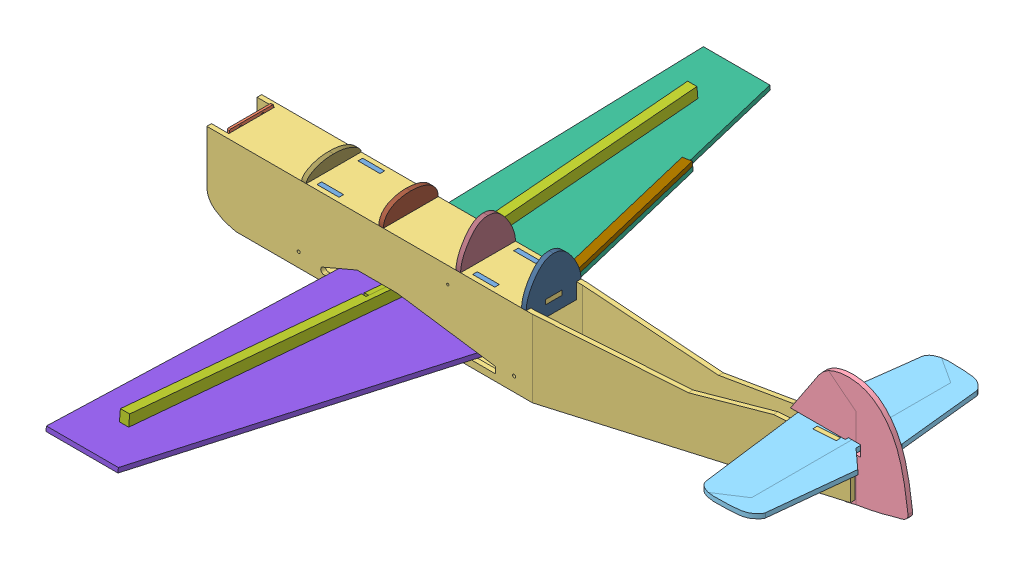
SolidWorks assembly BF109, configuration Default. Lengths in mm.
Overall size (779.28 215.67 760.08).
18 component instances, 14 part files, 17 mates.
Components (placement in the parent):
- Swappable Power Pod-1: Swappable Power Pod [Default] at origin size (334.33 44.96 52.58)
  - Swappable Power Pod-1: Swappable Power Pod [Default] at origin size (331.79 41.45 52.58)
  - 3D Printed Firewall-1: 3D Printed Firewall [Default] at (-149.3838 22.733 0) x (0 0 -1) z (0 -1 0) size (50.8 27.94 44.45)
- BF109_Fuselage-1: BF109_Fuselage [Default] at (-166.8438 41.4528 26.289) size (717.99 114.65 63.25)
- BF109_Tail-1: BF109_Tail [Default] at (474.0399 63.7309 0) size (135.74 127.69 270.43)
  - BF109_Rudder-1: BF109_Rudder [Default] at origin size (135.74 127.69 5.33)
  - BF109_Elevator-1: BF109_Elevator [Default] at (10.9958 -1.327 0) size (91.95 5.33 270.43)
- Part5^BF109-1: Part5^BF109 [Default] at origin size (2138.67 989.27 0) (hidden, virtual)
- BF109_Wing-1: BF109_Wing [Default] at (-25.8538 -41.5889 0) x (0 0.087156 -0.996195) z (1 0 0) size (755.05 90.58 170.24)
  - BF109_RightWing-1: BF109_RightWing [Default] at origin size (380.42 5.33 170.24)
  - BF109_Spar-1: BF109_Spar [Default] at origin size (375.56 25.75 10.67)
  - BF109_LeftWing-1: BF109_LeftWing [Default] at (0.9262 5.253 0) x (-0.984808 0.173648 0) z (0 0 1) size (380.42 5.33 170.24)
  - BF109_Spar-2: BF109_Spar [Default] at (0 0 119.8911) x (-0.984808 0.173648 0) z (0 0 -1) size (375.56 25.75 10.67)
  - BF109_WingSpacer-1: BF109_WingSpacer [Default] at (0 5.334 0) x (1 0 0) z (0 1 0) size (266.31 56.08 5.33)
- Former1-1: Former1 [Default] at (195.7891 41.4528 26.289) x (0 0 -1) z (1 0 0) size (63.25 59.44 5.33)
- Former3-1: Former3 [Default] at (31.2997 0 0) x (0 0 -1) z (1 0 0) size (63.25 26.92 5.33)
- Former4-1: Former4 [Default] at (-57.6003 0 0) x (0 0 -1) z (1 0 0) size (63.25 19.3 5.33)
- Former2-1: Former2 [Default] at (120.1997 41.4528 26.289) x (0 0 -1) z (1 0 0) size (63.25 46.74 5.33)
Mates (geometry in assembly coordinates):
- Coincident2: coincident anti-aligned: plane of Swappable Power Pod-1/Swappable Power Pod-1 through (-146.8438 5.334 26.289) normal (0 0 1); plane of BF109_Fuselage-1 through (-166.8438 41.4528 26.289) normal (0 0 -1)
- Coincident4: coincident aligned: plane of BF109_Tail-1/BF109_Rudder-1 through (474.0399 63.7309 0) normal (0 0 1); plane of assembly through (0 0 0) normal (0 0 1)
- Coincident5: coincident anti-aligned: plane of BF109_Fuselage-1 through (-165.0687 62.4039 52.0333) normal (0 1 0); plane of BF109_Tail-1/BF109_Elevator-1 through (485.0356 62.4039 0) normal (0 -1 0)
- Distance2: distance = 1.27 mm: line of BF109_Tail-1/BF109_Rudder-1 through (552.0566 8.8195 2.667) axis (0 1 0); plane of BF109_Fuselage-1 through (550.7841 41.4528 2.675) normal (0.997631 0 -0.068787)
- Coincident6: coincident anti-aligned: plane of Swappable Power Pod-1/3D Printed Firewall-1 through (-146.8438 1.778 24.13) normal (1 0 0); plane of BF109_Fuselage-1 through (-146.8438 36.1188 26.289) normal (-1 0 0)
- Distance5: distance = 1.905 mm aligned: plane of Swappable Power Pod-1/3D Printed Firewall-1 through (-146.8438 44.958 24.13) normal (0 1 0); plane of BF109_Fuselage-1 through (-166.8438 43.053 31.623) normal (0 1 0)
- Coincident9: coincident: line of BF109_Fuselage-1 through (-31.7768 -39.289 -26.289) axis (1 0 0); plane of BF109_Wing-1/BF109_RightWing-1 through (-25.8538 -41.5889 0) normal (0 -0.996195 -0.087156)
- Coincident10: coincident: line of BF109_Fuselage-1 through (-31.7768 -39.289 26.289) axis (1 0 0); plane of BF109_Wing-1/BF109_LeftWing-1 through (-25.8538 -41.5889 0) normal (0 -0.996195 0.087156)
- Coincident11: coincident: line of BF109_Wing-1/BF109_LeftWing-1 through (-25.8538 -41.5889 0) axis (1 0 0); plane of assembly
- Coincident13: coincident aligned: plane of Swappable Power Pod-1/Swappable Power Pod-1 through (0 41.4528 20.955) normal (0 1 0); plane of BF109_Fuselage-1 through (-166.8438 41.4528 31.623) normal (0 1 0)
- InPlace2: in place: plane of BF109_Fuselage-1 through (195.7891 36.1188 26.289) normal (1 0 0); plane of ? through (195.7891 0 0) normal (1 0 0); moOrthogonalPlaneRef_w of BF109_Fuselage-1 through (195.7891 36.1188 26.289) normal (1 0 0); line of ? through (-50 195.7891 0) axis (0 0 1); plane of BF109_Fuselage-1 through (195.7891 36.1188 26.289) normal (1 0 0); plane of ? through (195.7891 0 0) normal (0 0 -1); plane of BF109_Fuselage-1 through (195.7891 36.1188 26.289) normal (1 0 0); unknown of Former1-1
- Coincident17: coincident aligned: plane of BF109_Fuselage-1; plane of Former1-1
- Coincident18: coincident aligned: moOrthogonalPlaneRef_w of BF109_Fuselage-1 through (195.7891 41.4528 26.289) normal (0 1 0); plane of Former1-1
- Coincident19: coincident anti-aligned: moOrthogonalPlaneRef_w of BF109_Fuselage-1 through (195.7891 41.4528 26.289) normal (0 0 1); plane of Former1-1 through (195.7891 41.4528 26.289) normal (0 0 -1)
- Coincident20: coincident anti-aligned: plane of BF109_Fuselage-1 through (120.1997 -46.91 -12.7) normal (0 0 1); plane of Former2-1 through (125.5337 41.4528 -12.7) normal (0 0 -1)
- Coincident21: coincident anti-aligned: plane of BF109_Fuselage-1 through (-166.8438 41.4528 31.623) normal (0 1 0); plane of Former2-1 through (125.5337 41.4528 26.289) normal (0 -1 0)
- Coincident22: coincident anti-aligned: plane of BF109_Fuselage-1 through (125.5337 -46.91 12.7) normal (-1 0 0); plane of Former2-1 through (125.5337 41.4528 26.289) normal (1 0 0)
